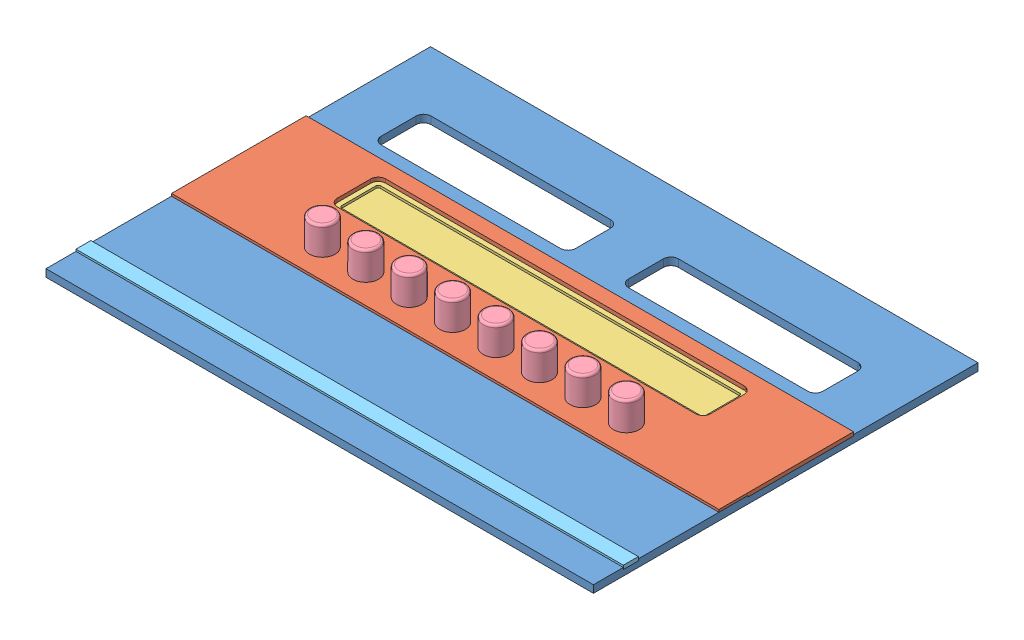
SolidWorks assembly Dual_Pokey_Prosystem, configuration Default. Lengths in mm.
Overall size (232.41 45.43 163.27).
5 component instances, 5 part files, 12 mates.
Components (placement in the parent):
- Panel-1: Panel [Default] at (70.739 117.1177 189.6753) size (232.41 3.17 163.27)
- trim-1: trim [Default] at (70.739 116.5589 189.4454) size (232.41 1.59 57.15)
- LCD-1: LCD [Default] at (57.5114 105.9927 163.6923) size (182 13.6 33.5)
- enc_brd-1: enc_brd [Default] at (-11.3289 93.3007 231.657) x (1 0 0) z (0 1 0) size (165.1 35.56 45.43)
- lower_trim-1: lower_trim [Default] at (70.739 116.3557 255.4359) size (232.41 1.59 6.35)
Mates (geometry in assembly coordinates):
- Distance2: distance = 0.5588 mm anti-aligned: plane of Panel-1 through (70.739 117.1177 189.6753) normal (0 1 0); plane of trim-1 through (70.739 116.5589 189.4454) normal (0 -1 0)
- Coincident2: coincident aligned: plane of Panel-1 through (186.944 113.9427 271.3109) normal (1 0 0); plane of trim-1 through (186.944 118.1464 218.0204) normal (1 0 0)
- Width1: width anti-aligned: plane of Panel-1 through (-10.9614 113.9427 192.957) normal (0 0 -1); plane of Panel-1 through (-10.9614 113.9427 162.0579) normal (0 0 1); plane of trim-1 through (-8.509 116.5589 167.2204) normal (0 0 1); plane of trim-1 through (-8.509 116.5589 187.7944) normal (0 0 -1)
- Concentric1: concentric aligned: cylinder of Panel-1 through (-19.261 113.9427 164.2575) axis (0 1 0) radius 1.75; cylinder of LCD-1 through (-19.261 105.9927 164.2575) axis (0 1 0) radius 1.75
- Concentric2: concentric aligned: cylinder of Panel-1 through (155.739 113.9427 190.7575) axis (0 1 0) radius 1.75; cylinder of LCD-1 through (155.739 105.9927 190.7575) axis (0 1 0) radius 1.75
- Distance1: distance = 6.35 mm anti-aligned: plane of Panel-1 through (70.739 113.9427 189.6753) normal (0 -1 0); plane of LCD-1 through (-22.761 107.5927 194.2575) normal (0 1 0)
- Distance3: distance = 19.05 mm anti-aligned: plane of enc_brd-1 through (-11.3289 94.8927 231.657) normal (0 1 0); plane of Panel-1 through (70.739 113.9427 189.6753) normal (0 -1 0)
- Concentric3: concentric anti-aligned: cylinder of Panel-1 through (6.2098 113.9427 205.657) axis (0 1 0) radius 5.9207; cylinder of enc_brd-1 through (6.2098 130.0971 205.657) axis (0 -1 0) radius 5.42
- Parallel1: parallel anti-aligned: cylinder of Panel-1 through (135.2748 113.9427 205.657) axis (0 1 0) radius 5.9207; cylinder of enc_brd-1 through (135.2723 130.0971 205.657) axis (0 -1 0) radius 5.42
- Distance4: distance = 0.762 mm anti-aligned: plane of lower_trim-1 through (70.739 116.3557 255.4359) normal (0 -1 0); plane of Panel-1 through (70.739 117.1177 189.6753) normal (0 1 0)
- Coincident4: coincident aligned: plane of Panel-1 through (-45.466 113.9427 271.3109) normal (-1 0 0); plane of lower_trim-1 through (-45.466 117.9432 258.6109) normal (-1 0 0)
- Distance5: distance = 12.7 mm aligned: plane of lower_trim-1 through (186.944 117.9432 258.6109) normal (0 0 1); plane of Panel-1 through (186.944 113.9427 271.3109) normal (0 0 1)
